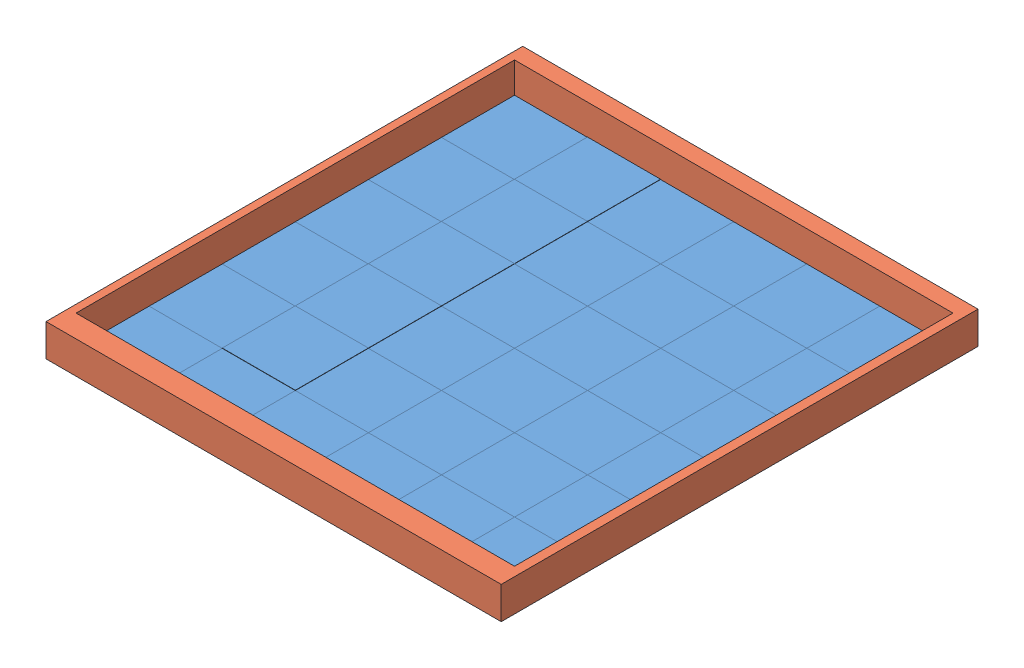
SolidWorks assembly Basic course world, configuration Default. Lengths in mm.
Overall size (1900 157.48 1990).
128 component instances, 46 part files, 70 mates.
Components (placement in the parent):
- Basic wood title-1: Basic wood title [Default] at (-72.9907 138.0771 103.8703) size (305 30 305)
- Basic wood title-2: Basic wood title [Default] at (841.8237 138.0771 -201.3152) x (1 0 -0.000304) z (0.000304 0 1) size (305 30 305)
- Basic wood title-3: Basic wood title [Default] at (536.5455 138.0771 -1116.2224) x (1 0 -0.000304) z (0.000304 0 1) size (305 30 305)
- Basic wood title-4: Basic wood title [Default] at (841.9165 138.0771 103.6848) x (1 0 -0.000304) z (0.000304 0 1) size (305 30 305)
- Basic wood title-5: Basic wood title [Default] at (1146.9165 138.0771 103.592) x (1 0 -0.000304) z (0.000304 0 1) size (305 30 305)
- Basic wood title-6: Basic wood title [Default] at (536.9165 138.0771 103.7776) x (1 0 -0.000304) z (0.000304 0 1) size (305 30 305)
- Basic wood title-7: Basic wood title [Default] at (1146.731 138.0771 -506.4079) x (1 0 -0.000304) z (0.000304 0 1) size (305 30 305)
- Basic wood title-9: Basic wood title [Default] at (841.5455 138.0771 -1116.3151) x (1 0 -0.000304) z (0.000304 0 1) size (305 30 305)
- Basic wood title-10: Basic wood title [Default] at (1146.8237 138.0771 -201.4079) x (1 0 -0.000304) z (0.000304 0 1) size (305 30 305)
- Basic wood title-11: Basic wood title [Default] at (1146.6382 138.0771 -811.4079) x (1 0 -0.000304) z (0.000304 0 1) size (305 30 305)
- Basic wood title-12: Basic wood title [Default] at (232.0093 139.2513 -201.1297) x (1 0 -0.000304) z (0.000304 0 1) size (305 30 305)
- Basic wood title-14: Basic wood title [Default] at (-72.9907 138.0771 -1421.1297) size (305 30 305)
- Basic wood title-15: Basic wood title [Default] at (841.731 138.0771 -506.3152) x (1 0 -0.000304) z (0.000304 0 1) size (305 30 305)
- Basic wood title-16: Basic wood title [Default] at (1451.731 138.0771 -506.5007) x (1 0 -0.000304) z (0.000304 0 1) size (305 30 305)
- Basic wood title-17: Basic wood title [Default] at (1451.4527 138.0771 -1421.5006) x (1 0 -0.000304) z (0.000304 0 1) size (305 30 305)
- Basic wood title-18: Basic wood title [Default] at (231.5455 139.2513 -1116.1296) x (1 0 -0.000304) z (0.000304 0 1) size (305 30 305)
- Basic wood title-20: Basic wood title [Default] at (536.6382 138.0771 -811.2224) x (1 0 -0.000304) z (0.000304 0 1) size (305 30 305)
- Basic wood title-21: Basic wood title [Default] at (841.6382 138.0771 -811.3152) x (1 0 -0.000304) z (0.000304 0 1) size (305 30 305)
- Basic wood title-22: Basic wood title [Default] at (1451.8237 138.0771 -201.5007) x (1 0 -0.000304) z (0.000304 0 1) size (305 30 305)
- Basic wood title-23: Basic wood title [Default] at (231.9165 139.2513 -506.1297) x (1 0 -0.000304) z (0.000304 0 1) size (305 30 305)
- Basic wood title-24: Basic wood title [Default] at (-72.9907 138.0771 -1116.1297) size (305 30 305)
- Basic wood title-25: Basic wood title [Default] at (1146.5455 138.0771 -1116.4079) x (1 0 -0.000304) z (0.000304 0 1) size (305 30 305)
- Basic wood title-26: Basic wood title [Default] at (-72.9907 138.0771 -201.1297) size (305 30 305)
- Basic wood title-27: Basic wood title [Default] at (1451.9165 138.0771 103.4993) x (1 0 -0.000304) z (0.000304 0 1) size (305 30 305)
- Basic wood title-28: Basic wood title [Default] at (536.731 138.0771 -506.2224) x (1 0 -0.000304) z (0.000304 0 1) size (305 30 305)
- Basic wood title-29: Basic wood title [Default] at (231.8237 139.2513 -811.1297) x (1 0 -0.000304) z (0.000304 0 1) size (305 30 305)
- Basic wood title-30: Basic wood title [Default] at (231.4527 139.2513 -1421.1296) x (1 0 -0.000304) z (0.000304 0 1) size (305 30 305)
- Basic wood title-31: Basic wood title [Default] at (536.4527 138.0771 -1421.2224) x (1 0 -0.000304) z (0.000304 0 1) size (305 30 305)
- Basic wood title-33: Basic wood title [Default] at (1146.4526 138.0771 -1421.4079) x (1 0 -0.000304) z (0.000304 0 1) size (305 30 305)
- Basic wood title-34: Basic wood title [Default] at (1451.5454 138.0771 -1116.5007) x (1 0 -0.000304) z (0.000304 0 1) size (305 30 305)
- Basic wood title-35: Basic wood title [Default] at (231.9165 138.0771 103.8703) x (1 0 -0.000304) z (0.000304 0 1) size (305 30 305)
- Basic wood title-36: Basic wood title [Default] at (536.8238 138.0771 -201.2224) x (1 0 -0.000304) z (0.000304 0 1) size (305 30 305)
- Basic wood title-37: Basic wood title [Default] at (-72.9907 138.0771 -506.1297) size (305 30 305)
- Basic wood title-38: Basic wood title [Default] at (1451.6382 138.0771 -811.5007) x (1 0 -0.000304) z (0.000304 0 1) size (305 30 305)
- Basic wood title-39: Basic wood title [Default] at (841.4527 138.0771 -1421.3151) x (1 0 -0.000304) z (0.000304 0 1) size (305 30 305)
- Basic wood title-40: Basic wood title [Default] at (-72.9907 138.0771 -811.1297) size (305 30 305)
- Cardboard walls-1: Cardboard walls [Default] at (-331.3215 160.5598 -1587.3117) size (1900 135 1990)
- CD Full MTE380-Assmebly.STEP-1: CD Full MTE380-Assmebly.STEP [Default] at (133.553 252.7867 -1226.6703) x (-0.999048 0 0.043619) z (-0.043619 0 -0.999048) size (200 141.83 218.21)
  - arduino_MEGA2560.STEP.STEP-1: arduino_MEGA2560.STEP.STEP [Default] at (-61.674 55.6712 65.8617) x (-0.034895 0.0087 0.999353) z (-0.99939 0.000685 -0.034902) size (53.34 15.25 107.96) (hidden)
    - MEGAboard.STEP.STEP-1: MEGAboard.STEP.STEP [Default] at origin size (53.34 1.6 101.6)
    - 47uf CAP Dcase.STEP.STEP-1: 47uf CAP Dcase.STEP.STEP [Default] at (-9.144 0 -18.415) x (0 0 -1) z (1 0 0) size (7.2 5.81 8)
    - USB SHELL.STEP.STEP-1: USB SHELL.STEP.STEP [Default] at (-38.02 0.43 6.35) size (14.09 15.2 16.51)
    - USB core.STEP.STEP-1: USB core.STEP.STEP [Default] at (-38.02 0.43 6.35) size (11.3 10.68 15.75)
    - usb top contact.STEP.STEP-1: usb top contact.STEP.STEP [Default] at (-36.77 6.52 5.97) size (1 9.67 13.76)
    - usb btm contact.STEP.STEP-1: usb btm contact.STEP.STEP [Default] at (-36.77 4.84 5.97) size (1 6.84 11.76)
    - usb btm contact.STEP.STEP-2: usb btm contact.STEP.STEP [Default] at (-39.27 4.84 5.97) size (1 6.84 11.76)
    - usb top contact.STEP.STEP-2: usb top contact.STEP.STEP [Default] at (-39.27 6.52 5.97) size (1 9.67 13.76)
    - power jack.STEP.STEP-1: power jack.STEP.STEP [Default] at (-7.675 0 1.905) size (11.2 15.2 15.9)
    - 47uf CAP Dcase.STEP.STEP-2: 47uf CAP Dcase.STEP.STEP [Default] at (-9.144 0 -25.527) x (0 0 -1) z (1 0 0) size (7.2 5.81 8)
    - crystal.STEP.STEP-1: crystal.STEP.STEP [Default] at (-26.035 0 -18.415) x (1 0 0) z (0 0 -1) size (4 5 11)
    - 2pin_header__02.STEP.STEP-1: 2pin_header__02.STEP.STEP [Default] at (-46.23 0 -15.75) size (5 11.75 2.54)
    - reg.STEP.STEP-1: reg.STEP.STEP [Default] at (-17.78 0 -8.636) size (6.5 1.69 8.3)
    - led.STEP.STEP-1: led.STEP.STEP [Default] at (-34.29 0 -27.94) x (0 0 1) z (-1 0 0) size (4 0.9 1.55)
    - 2pin_header__02.STEP.STEP-2: 2pin_header__02.STEP.STEP [Default] at (-30.43 0 -64.91) x (0 0 1) z (-1 0 0) size (5 11.75 2.54)
    - 2pin_header__02.STEP.STEP-3: 2pin_header__02.STEP.STEP [Default] at (-27.89 0 -64.91) x (0 0 1) z (-1 0 0) size (5 11.75 2.54)
    - 2pin_header__02.STEP.STEP-4: 2pin_header__02.STEP.STEP [Default] at (-25.35 0 -64.91) x (0 0 1) z (-1 0 0) size (5 11.75 2.54)
    - 2pin_header__02.STEP.STEP-5: 2pin_header__02.STEP.STEP [Default] at (-46.23 0 -18.29) size (5 11.75 2.54)
    - 2pin_header__02.STEP.STEP-6: 2pin_header__02.STEP.STEP [Default] at (-46.23 0 -20.83) size (5 11.75 2.54)
    - atmega16u2.STEP.STEP-1: atmega16u2.STEP.STEP [Default] at (-34.671 0.06 -20) x (1 0 0) z (0 0 -1) size (5.5 1.01 5.5)
    - led.STEP.STEP-2: led.STEP.STEP [Default] at (-36.576 0 -27.94) x (0 0 -1) z (1 0 0) size (4 0.9 1.55)
    - led.STEP.STEP-3: led.STEP.STEP [Default] at (-42.164 0 -27.94) x (0 0 1) z (-1 0 0) size (4 0.9 1.55)
    - led.STEP.STEP-4: led.STEP.STEP [Default] at (-36.83 0 -76.2) x (0 0 1) z (-1 0 0) size (4 0.9 1.55)
    - 8 PORT HEADER.STEP.STEP-1: 8 PORT HEADER.STEP.STEP [Default] at (-50.8 0 -45.72) x (0 0 -1) z (1 0 0) size (20.32 10.51 2.41)
    - 8 PORT HEADER.STEP.STEP-2: 8 PORT HEADER.STEP.STEP [Default] at (-2.54 0 -27.94) x (0 0 -1) z (1 0 0) size (20.32 10.51 2.41)
    - 8 PORT HEADER.STEP.STEP-3: 8 PORT HEADER.STEP.STEP [Default] at (-2.54 0 -50.8) x (0 0 -1) z (1 0 0) size (20.32 10.51 2.41)
    - 10 PORT HEADER.STEP.STEP-1: 10 PORT HEADER.STEP.STEP [Default] at (-50.8 0 -18.796) x (0 0 -1) z (1 0 0) size (25.4 10.51 2.41)
    - 102 RESISTOR PACK.STEP.STEP-1: 102 RESISTOR PACK.STEP.STEP [Default] at (-36.83 0 -80.645) size (3.2 0.51 3)
    - 102 RESISTOR PACK.STEP.STEP-2: 102 RESISTOR PACK.STEP.STEP [Default] at (-39.37 0 -27.94) size (3.2 0.51 3)
    - 103 RESISTOR PACK.STEP.STEP-1: 103 RESISTOR PACK.STEP.STEP [Default] at (-31.115 0 -27.94) size (3.2 0.51 3)
    - 220 RESISTOR PACK.STEP.STEP-1: 220 RESISTOR PACK.STEP.STEP [Default] at (-37.084 0 -12.065) size (3.2 0.51 3)
    - 16mhz crystal - measured.STEP.STEP-1: 16mhz crystal - measured.STEP.STEP [Default] at (-14.605 0 -38.354) size (3.4 0.8 2)
    - PADS001.STEP.STEP-1: PADS001.STEP.STEP [Default] at (-39.878 0.1 -18.288) x (-1 0 0) z (0 0 1) size (4.54 0.1 4.54)
    - 603 cap on pad.STEP.STEP-1: 603 cap on pad.STEP.STEP [Default] at (-44.45 0 -27.94) x (0 0 -1) z (1 0 0) size (2.76 0.91 1.03)
    - ssot3.STEP.STEP-1: ssot3.STEP.STEP [Default] at (-25.908 0 -9.144) x (-1 0 0) z (0 0 -1) size (3 1.13 3.09)
    - mf-msmf050-2.STEP.STEP-1: mf-msmf050-2.STEP.STEP [Default] at (-26.67 0 -4.445) size (6.12 1.1 3.72)
    - 603 cap on pad.STEP.STEP-2: 603 cap on pad.STEP.STEP [Default] at (-29.337 0 -24.765) x (0 0 1) z (-1 0 0) size (2.76 0.91 1.03)
    - 603 cap on pad.STEP.STEP-3: 603 cap on pad.STEP.STEP [Default] at (-30.988 0 -12.065) x (0 0 -1) z (1 0 0) size (2.76 0.91 1.03)
    - lmv358.STEP.STEP-1: lmv358.STEP.STEP [Default] at (-25.146 0 -27.94) size (3.7 1.4 2.9)
    - 603 cap on pad.STEP.STEP-4: 603 cap on pad.STEP.STEP [Default] at (-17.653 0 -14.351) size (2.76 0.91 1.03)
    - 603 cap on pad.STEP.STEP-5: 603 cap on pad.STEP.STEP [Default] at (-29.337 0 -12.065) x (0 0 1) z (-1 0 0) size (2.76 0.91 1.03)
    - 603 cap on pad.STEP.STEP-6: 603 cap on pad.STEP.STEP [Default] at (-29.337 0 -21.59) x (0 0 1) z (-1 0 0) size (2.76 0.91 1.03)
    - 603 cap on pad.STEP.STEP-7: 603 cap on pad.STEP.STEP [Default] at (-29.337 0 -15.24) x (0 0 1) z (-1 0 0) size (2.76 0.91 1.03)
    - 603 cap on pad.STEP.STEP-8: 603 cap on pad.STEP.STEP [Default] at (-42.291 0 -12.065) x (0 0 1) z (-1 0 0) size (2.76 0.91 1.03)
    - lp2985dgkr.STEP.STEP-1: lp2985dgkr.STEP.STEP [Default] at (-21.336 0 -18.415) x (0 0 -1) z (1 0 0) size (5.85 1.1 3)
    - cd1206 diode.STEP.STEP-1: cd1206 diode.STEP.STEP [Default] at (-14.605 0 -35.56) x (0 0 1) z (-1 0 0) size (2.01 0.96 5)
    - cd1206 diode.STEP.STEP-2: cd1206 diode.STEP.STEP [Default] at (-46.228 0 -13.081) x (0 0 1) z (-1 0 0) size (2.01 0.96 5)
    - 603 resistor.STEP.STEP-1: 603 resistor.STEP.STEP [Default] at (-29.337 0 -18.415) x (0 0 1) z (-1 0 0) size (2.36 0.61 1.02)
    - blm21.STEP.STEP-1: blm21.STEP.STEP [Default] at (-45.085 0 -8.255) x (0 0 -1) z (1 0 0) size (2.78 0.95 1.32)
    - m7 diode.STEP.STEP-1: m7 diode.STEP.STEP [Default] at (-2.794 0 -21.59) x (0 0 -1) z (1 0 0) size (6.66 2.35 2.5)
    - MLC0603.STEP.STEP-1: MLC0603.STEP.STEP [Default] at (-34.29 0 -12.065) x (0 0 -1) z (1 0 0) size (2.36 0.6 1.02)
    - MLC0603.STEP.STEP-2: MLC0603.STEP.STEP [Default] at (-39.878 0 -12.065) x (0 0 -1) z (1 0 0) size (2.36 0.6 1.02)
    - RESET CORE.STEP.STEP-1: RESET CORE.STEP.STEP [Default] at (-27.94 0.1 -74.168) x (0 0 1) z (-1 0 0) size (6.2 3.1 9.6)
    - RESET.STEP.STEP-1: RESET.STEP.STEP [Default] at (-27.94 0.1 -74.168) size (7.3 2 6.2)
    - 8 PORT HEADER.STEP.STEP-4: 8 PORT HEADER.STEP.STEP [Default] at (-2.54 0 -73.66) x (0 0 -1) z (1 0 0) size (20.32 10.51 2.41)
    - 8 PORT HEADER.STEP.STEP-5: 8 PORT HEADER.STEP.STEP [Default] at (-50.8 0 -68.58) x (0 0 -1) z (1 0 0) size (20.32 10.51 2.41)
    - 603 cap on pad.STEP.STEP-9: 603 cap on pad.STEP.STEP [Default] at (-21.59 0 -27.94) x (0 0 1) z (-1 0 0) size (2.76 0.91 1.03)
    - 603 cap on pad.STEP.STEP-10: 603 cap on pad.STEP.STEP [Default] at (-18.288 0 -27.94) x (0 0 1) z (-1 0 0) size (2.76 0.91 1.03)
    - 103 RESISTOR PACK.STEP.STEP-2: 103 RESISTOR PACK.STEP.STEP [Default] at (-16.51 0 -18.415) size (3.2 0.51 3)
    - 603 cap on pad.STEP.STEP-11: 603 cap on pad.STEP.STEP [Default] at (-17.145 0 -21.59) x (0 0 -1) z (1 0 0) size (2.76 0.91 1.03)
    - 603 cap on pad.STEP.STEP-12: 603 cap on pad.STEP.STEP [Default] at (-39.37 0 -58.928) x (0 0 1) z (-1 0 0) size (2.76 0.91 1.03)
    - 603 cap on pad.STEP.STEP-13: 603 cap on pad.STEP.STEP [Default] at (-14.605 0 -33.528) size (2.76 0.91 1.03)
    - 603 resistor.STEP.STEP-2: 603 resistor.STEP.STEP [Default] at (-14.605 0 -40.513) x (-1 0 0) z (0 0 -1) size (2.36 0.61 1.02)
    - 603 cap on pad.STEP.STEP-14: 603 cap on pad.STEP.STEP [Default] at (-7.112 0 -38.608) x (0 0 1) z (-1 0 0) size (2.76 0.91 1.03)
    - 603 cap on pad.STEP.STEP-15: 603 cap on pad.STEP.STEP [Default] at (-30.4038 0 -40.0558) x (0 0 1) z (-1 0 0) size (2.76 0.91 1.03)
    - 18 X 2 ROW HEADER.STEP.STEP-1: 18 X 2 ROW HEADER.STEP.STEP [Default] at (-50.8 0 -95.25) size (45.72 10.51 4.95)
    - atmega2650-16AU.STEP.STEP-1: atmega2650-16AU.STEP.STEP [Default] at (-28.3464 0.1 -50.8) x (0 0 1) z (-1 0 0) size (16.81 1.11 16.81)
  - MTE380-Housing.STEP-1: MTE380-Housing.STEP [Default] at origin size (98 65 165) (hidden)
  - hc-sr04_Detailed.STEP-1: hc-sr04_Detailed.STEP [Default] at (0 39.7 90.35) x (-1 0 0) z (0 1 0) size (45.2 18.55 25.75) (hidden)
  - MTE380-Base.STEP-1: MTE380-Base.STEP [Default] at (0 -10 7) x (0 0 -1) z (1 0 0) size (178 85 146) (hidden)
  - 6V_30-1_micro metal gearmotor.STEP-1: 6V_30-1_micro metal gearmotor.STEP [Default] at (-68 -15 -42) x (0 -1 0) z (0 0 1) size (10 34 12) (hidden)
  - Pololu 3mm to 12mm hex adapter.STEP-1: Pololu 3mm to 12mm hex adapter.STEP [Default] at (-91 -15 -42) x (0 0 -1) z (0 -1 0) size (13.88 17.03 13.86) (hidden)
  - 6V_30-1_micro metal gearmotor.STEP-2: 6V_30-1_micro metal gearmotor.STEP [Default] at (-68 -15 56) x (0 1 0) z (0 0 -1) size (10 34 12) (hidden)
  - 6V_30-1_micro metal gearmotor.STEP-3: 6V_30-1_micro metal gearmotor.STEP [Default] at (68 -15 -42) x (0 -1 0) z (0 0 -1) size (10 34 12) (hidden)
  - 6V_30-1_micro metal gearmotor.STEP-4: 6V_30-1_micro metal gearmotor.STEP [Default] at (68 -15 56) x (0 -1 0) z (0 0 -1) size (10 34 12) (hidden)
  - Pololu 3mm to 12mm hex adapter.STEP-2: Pololu 3mm to 12mm hex adapter.STEP [Default] at (-91 -15 56) x (0 0 -1) z (0 -1 0) size (13.88 17.03 13.86) (hidden)
  - Pololu 3mm to 12mm hex adapter.STEP-3: Pololu 3mm to 12mm hex adapter.STEP [Default] at (91 -15 -42) x (0 0 1) z (0 -1 0) size (13.88 17.03 13.86) (hidden)
  - Pololu 3mm to 12mm hex adapter.STEP-4: Pololu 3mm to 12mm hex adapter.STEP [Default] at (91 -15 56) x (0 0 1) z (0 -1 0) size (13.88 17.03 13.86) (hidden)
  - 88mm 12mm hex wheel.STEP-1: 88mm 12mm hex wheel.STEP [Default] at (-100 -15 -42) x (0 -0.866025 0.5) z (0 0.5 0.866025) size (88 40 88) (hidden)
  - 88mm 12mm hex wheel.STEP-2: 88mm 12mm hex wheel.STEP [Default] at (100 -15 -42) x (0 0.866025 -0.5) z (0 0.5 0.866025) size (88 40 88) (hidden)
  - 88mm 12mm hex wheel_32mm variant.STEP-1: 88mm 12mm hex wheel_32mm variant.STEP [Default] at (-100 -15 56) x (0 0 -1) z (0 -1 0) size (88 32 88) (hidden)
  - 88mm 12mm hex wheel_32mm variant.STEP-2: 88mm 12mm hex wheel_32mm variant.STEP [Default] at (100 -15 56) x (0 0.866025 0.5) z (0 -0.5 0.866025) size (88 32 88) (hidden)
  - Micro Metal motor Mount.STEP-1: Micro Metal motor Mount.STEP [Default] at (-56 -20 -42) x (0 0 1) z (-1 0 0) size (32.4 11.7 12) (hidden)
  - Micro Metal motor Mount.STEP-2: Micro Metal motor Mount.STEP [Default] at (-55.12 -20 56) x (0 0 1) z (-1 0 0) size (32.4 11.7 12) (hidden)
  - Micro Metal motor Mount.STEP-3: Micro Metal motor Mount.STEP [Default] at (68 -20 56) x (0 0 1) z (-1 0 0) size (32.4 11.7 12) (hidden)
  - Micro Metal motor Mount.STEP-4: Micro Metal motor Mount.STEP [Default] at (64.0501 -20 -42) x (0 0 1) z (-1 0 0) size (32.4 11.7 12) (hidden)
  - HalfBreadboard.step.STEP-1: HalfBreadboard.step.STEP [Default] at (-4.201 55.0971 22.2235) x (0.008727 0 0.999962) z (-0.999962 0 0.008727) size (56.09 12.95 83.02) (hidden)
  - Adafruit_BNO055.STEP-1: Adafruit_BNO055.STEP [Default] at (-17.1891 60.0611 -9.3281) size (26.67 4.2 20.32) (hidden)
  - LiPo Sunpadow 3S Lipo Battery 11.1V 35C 35 20 75.STEP-1: LiPo Sunpadow 3S Lipo Battery 11.1V 35C 35 20 75.STEP [Default] at (-22.8253 1.205 34.1251) x (-0.026177 0 0.999657) z (-0.999657 0 -0.026177) size (75 20 35) (hidden)
Mates (geometry in assembly coordinates):
- Coincident3: coincident anti-aligned: line of Basic wood title-1 through (232.0093 138.0771 103.8703) axis (-1 0 0); line of Basic wood title-26 through (-72.9907 138.0771 103.8703) axis (1 0 0)
- Coincident4: coincident aligned: line of Basic wood title-1 through (232.0093 168.0771 103.8703) axis (0 -1 0); line of Basic wood title-26 through (232.0093 168.0771 103.8703) axis (0 -1 0)
- Coincident11: coincident aligned: line of Basic wood title-12 through (232.0093 169.2513 -201.1297) axis (0 -1 0); line of Basic wood title-26 through (232.0093 168.0771 -201.1297) axis (0 -1 0)
- Coincident13: coincident: point of Basic wood title-1; point of Basic wood title-35
- Coincident27: coincident anti-aligned: line of Basic wood title-37 through (-72.9907 138.0771 -201.1297) axis (1 0 0); line of Basic wood title-26 through (232.0093 138.0771 -201.1297) axis (-1 0 0)
- Coincident28: coincident aligned: line of Basic wood title-12 through (232.0093 169.2513 -201.1297) axis (0 -1 0); line of Basic wood title-37 through (232.0093 168.0771 -201.1297) axis (0 -1 0)
- Coincident29: coincident anti-aligned: plane of Basic wood title-37 through (-72.9907 168.0771 -506.1297) normal (0 0 -1); plane of Basic wood title-40 through (-72.9907 168.0771 -506.1297) normal (0 0 1)
- Coincident30: coincident anti-aligned: line of Basic wood title-37 through (232.0093 138.0771 -506.1297) axis (-1 0 0); line of Basic wood title-40 through (-72.9907 138.0771 -506.1297) axis (1 0 0)
- Coincident31: coincident aligned: line of Basic wood title-37 through (232.0093 168.0771 -506.1297) axis (0 -1 0); line of Basic wood title-40 through (232.0093 168.0771 -506.1297) axis (0 -1 0)
- Coincident32: coincident anti-aligned: line of Basic wood title-24 through (-72.9907 138.0771 -811.1297) axis (1 0 0); line of Basic wood title-40 through (232.0093 138.0771 -811.1297) axis (-1 0 0)
- Coincident34: coincident aligned: line of Basic wood title-24 through (232.0093 168.0771 -811.1297) axis (0 -1 0); line of Basic wood title-40 through (232.0093 168.0771 -811.1297) axis (0 -1 0)
- Coincident35: coincident anti-aligned: line of Basic wood title-14 through (-72.9907 138.0771 -1116.1297) axis (1 0 0); line of Basic wood title-24 through (232.0093 138.0771 -1116.1297) axis (-1 0 0)
- Coincident36: coincident aligned: line of Basic wood title-14 through (232.0093 168.0771 -1116.1297) axis (0 -1 0); line of Basic wood title-24 through (232.0093 168.0771 -1116.1297) axis (0 -1 0)
- Coincident37: coincident anti-aligned: line of Basic wood title-6 through (536.9165 138.0771 103.7776) axis (0.000304 0 1); line of Basic wood title-35 through (537.0093 138.0771 408.7775) axis (-0.000304 0 -1)
- Coincident38: coincident aligned: line of Basic wood title-6 through (537.0093 168.0771 408.7775) axis (0 -1 0); line of Basic wood title-35 through (537.0093 168.0771 408.7775) axis (0 -1 0)
- Coincident39: coincident anti-aligned: line of Basic wood title-4 through (841.9165 138.0771 103.6848) axis (0.000304 0 1); line of Basic wood title-6 through (842.0093 138.0771 408.6848) axis (-0.000304 0 -1)
- Coincident40: coincident aligned: line of Basic wood title-4 through (842.0093 168.0771 408.6848) axis (0 -1 0); line of Basic wood title-6 through (842.0093 168.0771 408.6848) axis (0 -1 0)
- Coincident42: coincident anti-aligned: line of Basic wood title-4 through (1147.0093 138.0771 408.592) axis (-0.000304 0 -1); line of Basic wood title-5 through (1146.9165 138.0771 103.592) axis (0.000304 0 1)
- Coincident43: coincident aligned: line of Basic wood title-4 through (1146.9165 168.0771 103.592) axis (0 -1 0); line of Basic wood title-5 through (1146.9165 168.0771 103.592) axis (0 -1 0)
- Coincident44: coincident anti-aligned: line of Basic wood title-5 through (1452.0092 138.0771 408.4993) axis (-0.000304 0 -1); line of Basic wood title-27 through (1451.9165 138.0771 103.4993) axis (0.000304 0 1)
- Coincident45: coincident aligned: line of Basic wood title-5 through (1451.9165 168.0771 103.4993) axis (0 -1 0); line of Basic wood title-27 through (1451.9165 168.0771 103.4993) axis (0 -1 0)
- Coincident46: coincident anti-aligned: line of Basic wood title-6 through (841.9165 138.0771 103.6848) axis (-1 0 0.000304); line of Basic wood title-36 through (536.9165 138.0771 103.7776) axis (1 0 -0.000304)
- Coincident47: coincident aligned: line of Basic wood title-4 through (841.9165 168.0771 103.6848) axis (0 -1 0); line of Basic wood title-36 through (841.9165 168.0771 103.6848) axis (0 -1 0)
- Coincident48: coincident anti-aligned: line of Basic wood title-2 through (841.9165 138.0771 103.6848) axis (1 0 -0.000304); line of Basic wood title-4 through (1146.9165 138.0771 103.592) axis (-1 0 0.000304)
- Coincident49: coincident aligned: line of Basic wood title-2 through (1146.9165 168.0771 103.592) axis (0 -1 0); line of Basic wood title-5 through (1146.9165 168.0771 103.592) axis (0 -1 0)
- Coincident50: coincident anti-aligned: line of Basic wood title-5 through (1451.9165 138.0771 103.4993) axis (-1 0 0.000304); line of Basic wood title-10 through (1146.9165 138.0771 103.592) axis (1 0 -0.000304)
- Coincident51: coincident aligned: line of Basic wood title-10 through (1451.9165 168.0771 103.4993) axis (0 -1 0); line of Basic wood title-27 through (1451.9165 168.0771 103.4993) axis (0 -1 0)
- Coincident52: coincident anti-aligned: line of Basic wood title-22 through (1451.9165 138.0771 103.4993) axis (1 0 -0.000304); line of Basic wood title-27 through (1756.9165 138.0771 103.4065) axis (-1 0 0.000304)
- Coincident53: coincident aligned: line of Basic wood title-22 through (1756.9165 168.0771 103.4065) axis (0 -1 0); line of Basic wood title-27 through (1756.9165 168.0771 103.4065) axis (0 -1 0)
- Coincident54: coincident anti-aligned: line of Basic wood title-12 through (537.0093 139.2513 -201.2225) axis (-1 0 0.000304); line of Basic wood title-23 through (232.0093 139.2513 -201.1297) axis (1 0 -0.000304)
- Coincident55: coincident anti-aligned: line of Basic wood title-28 through (536.8238 138.0771 -201.2224) axis (1 0 -0.000304); line of Basic wood title-36 through (841.8237 138.0771 -201.3152) axis (-1 0 0.000304)
- Coincident56: coincident aligned: line of Basic wood title-12 through (232.0093 169.2513 -201.1297) axis (0 -1 0); line of Basic wood title-23 through (232.0093 169.2513 -201.1297) axis (0 -1 0)
- Coincident57: coincident aligned: line of Basic wood title-28 through (536.8238 168.0771 -201.2224) axis (0 -1 0); line of Basic wood title-36 through (536.8238 168.0771 -201.2224) axis (0 -1 0)
- Coincident58: coincident anti-aligned: line of Basic wood title-2 through (1146.8237 138.0771 -201.4079) axis (-1 0 0.000304); line of Basic wood title-15 through (841.8237 138.0771 -201.3152) axis (1 0 -0.000304)
- Coincident59: coincident aligned: line of Basic wood title-15 through (841.8237 168.0771 -201.3152) axis (0 -1 0); line of Basic wood title-28 through (841.8237 168.0771 -201.3152) axis (0 -1 0)
- Coincident60: coincident anti-aligned: line of Basic wood title-7 through (1146.8237 138.0771 -201.4079) axis (1 0 -0.000304); line of Basic wood title-10 through (1451.8237 138.0771 -201.5007) axis (-1 0 0.000304)
- Coincident61: coincident aligned: line of Basic wood title-7 through (1146.8237 168.0771 -201.4079) axis (0 -1 0); line of Basic wood title-10 through (1146.8237 168.0771 -201.4079) axis (0 -1 0)
- Coincident62: coincident anti-aligned: line of Basic wood title-16 through (1451.8237 138.0771 -201.5007) axis (1 0 -0.000304); line of Basic wood title-22 through (1756.8237 138.0771 -201.5935) axis (-1 0 0.000304)
- Coincident63: coincident aligned: line of Basic wood title-16 through (1756.8237 168.0771 -201.5935) axis (0 -1 0); line of Basic wood title-22 through (1756.8237 168.0771 -201.5935) axis (0 -1 0)
- Coincident64: coincident anti-aligned: line of Basic wood title-23 through (536.9165 139.2513 -506.2225) axis (-1 0 0.000304); line of Basic wood title-29 through (231.9165 139.2513 -506.1297) axis (1 0 -0.000304)
- Coincident65: coincident aligned: line of Basic wood title-23 through (536.9165 169.2513 -506.2225) axis (0 -1 0); line of Basic wood title-29 through (536.9165 169.2513 -506.2225) axis (0 -1 0)
- Coincident67: coincident anti-aligned: line of Basic wood title-20 through (536.731 138.0771 -506.2224) axis (1 0 -0.000304); line of Basic wood title-28 through (841.731 138.0771 -506.3152) axis (-1 0 0.000304)
- Coincident68: coincident aligned: line of Basic wood title-15 through (841.731 168.0771 -506.3152) axis (0 -1 0); line of Basic wood title-20 through (841.731 168.0771 -506.3152) axis (0 -1 0)
- Coincident69: coincident anti-aligned: line of Basic wood title-15 through (1146.731 138.0771 -506.4079) axis (-1 0 0.000304); line of Basic wood title-21 through (841.731 138.0771 -506.3152) axis (1 0 -0.000304)
- Coincident70: coincident aligned: line of Basic wood title-15 through (841.731 168.0771 -506.3152) axis (0 -1 0); line of Basic wood title-21 through (841.731 168.0771 -506.3152) axis (0 -1 0)
- Coincident71: coincident anti-aligned: line of Basic wood title-7 through (1451.731 138.0771 -506.5007) axis (-1 0 0.000304); line of Basic wood title-11 through (1146.731 138.0771 -506.4079) axis (1 0 -0.000304)
- Coincident72: coincident aligned: line of Basic wood title-7 through (1146.731 168.0771 -506.4079) axis (0 -1 0); line of Basic wood title-11 through (1146.731 168.0771 -506.4079) axis (0 -1 0)
- Coincident73: coincident anti-aligned: line of Basic wood title-16 through (1756.7309 138.0771 -506.5934) axis (-1 0 0.000304); line of Basic wood title-38 through (1451.731 138.0771 -506.5007) axis (1 0 -0.000304)
- Coincident74: coincident aligned: line of Basic wood title-16 through (1756.7309 168.0771 -506.5934) axis (0 -1 0); line of Basic wood title-38 through (1756.7309 168.0771 -506.5934) axis (0 -1 0)
- Coincident75: coincident anti-aligned: line of Basic wood title-18 through (231.6383 139.2513 -811.1296) axis (1 0 -0.000304); line of Basic wood title-29 through (536.8237 139.2513 -811.2225) axis (-1 0 0.000304)
- Coincident77: coincident aligned: line of Basic wood title-18 through (536.6382 169.2513 -811.2224) axis (0 -1 0); line of Basic wood title-20 through (536.6382 168.0771 -811.2224) axis (0 -1 0)
- Coincident78: coincident anti-aligned: line of Basic wood title-3 through (536.6382 138.0771 -811.2224) axis (1 0 -0.000304); line of Basic wood title-20 through (841.6382 138.0771 -811.3152) axis (-1 0 0.000304)
- Coincident79: coincident aligned: line of Basic wood title-3 through (841.6382 168.0771 -811.3152) axis (0 -1 0); line of Basic wood title-21 through (841.6382 168.0771 -811.3152) axis (0 -1 0)
- Coincident81: coincident anti-aligned: line of Basic wood title-9 through (841.6382 138.0771 -811.3152) axis (1 0 -0.000304); line of Basic wood title-21 through (1146.6382 138.0771 -811.4079) axis (-1 0 0.000304)
- Coincident82: coincident aligned: line of Basic wood title-3 through (841.6382 168.0771 -811.3152) axis (0 -1 0); line of Basic wood title-9 through (841.6382 168.0771 -811.3152) axis (0 -1 0)
- Coincident83: coincident anti-aligned: line of Basic wood title-11 through (1451.6382 138.0771 -811.5007) axis (-1 0 0.000304); line of Basic wood title-25 through (1146.6382 138.0771 -811.4079) axis (1 0 -0.000304)
- Coincident84: coincident aligned: line of Basic wood title-11 through (1451.6382 168.0771 -811.5007) axis (0 -1 0); line of Basic wood title-25 through (1451.6382 168.0771 -811.5007) axis (0 -1 0)
- Coincident85: coincident anti-aligned: line of Basic wood title-34 through (1451.6382 138.0771 -811.5007) axis (1 0 -0.000304); line of Basic wood title-38 through (1756.6382 138.0771 -811.5934) axis (-1 0 0.000304)
- Coincident86: coincident aligned: line of Basic wood title-34 through (1756.6382 168.0771 -811.5934) axis (0 -1 0); line of Basic wood title-38 through (1756.6382 168.0771 -811.5934) axis (0 -1 0)
- Coincident87: coincident anti-aligned: line of Basic wood title-18 through (536.5455 139.2513 -1116.2224) axis (-1 0 0.000304); line of Basic wood title-30 through (231.5455 139.2513 -1116.1296) axis (1 0 -0.000304)
- Coincident88: coincident aligned: line of Basic wood title-18 through (536.5455 169.2513 -1116.2224) axis (0 -1 0); line of Basic wood title-30 through (536.5455 169.2513 -1116.2224) axis (0 -1 0)
- Coincident89: coincident anti-aligned: line of Basic wood title-3 through (841.5455 138.0771 -1116.3151) axis (-1 0 0.000304); line of Basic wood title-31 through (536.5455 138.0771 -1116.2224) axis (1 0 -0.000304)
- Coincident90: coincident aligned: line of Basic wood title-9 through (841.5455 168.0771 -1116.3151) axis (0 -1 0); line of Basic wood title-31 through (841.5455 168.0771 -1116.3151) axis (0 -1 0)
- Coincident91: coincident anti-aligned: line of Basic wood title-9 through (1146.5455 138.0771 -1116.4079) axis (-1 0 0.000304); line of Basic wood title-39 through (841.5455 138.0771 -1116.3151) axis (1 0 -0.000304)
- Coincident92: coincident aligned: line of Basic wood title-25 through (1146.5455 168.0771 -1116.4079) axis (0 -1 0); line of Basic wood title-39 through (1146.5455 168.0771 -1116.4079) axis (0 -1 0)
- Coincident93: coincident anti-aligned: line of Basic wood title-25 through (1451.5454 138.0771 -1116.5007) axis (-1 0 0.000304); line of Basic wood title-33 through (1146.5454 138.0771 -1116.4079) axis (1 0 -0.000304)
- Coincident94: coincident: line of Basic wood title-33 through (1451.5454 168.0771 -1116.5007) axis (0 -1 0); plane of Basic wood title-34 through (1451.5454 168.0771 -1116.5007) normal (-0.000304 0 -1)
- Coincident95: coincident: line of Basic wood title-17 through (1451.5454 138.0771 -1116.5007) axis (1 0 -0.000304); moEndPointRef_w of Basic wood title-34
- Coincident96: coincident aligned: line of Basic wood title-17 through (1451.5454 168.0771 -1116.5007) axis (0 -1 0); line of Basic wood title-34 through (1451.5454 168.0771 -1116.5007) axis (0 -1 0)
- Coincident98: coincident anti-aligned: line of Basic wood title-1 through (-72.9907 168.0771 408.8703) axis (0 -1 0); line of Cardboard walls-1 through (-72.9907 160.5598 408.8703) axis (0 1 0)
